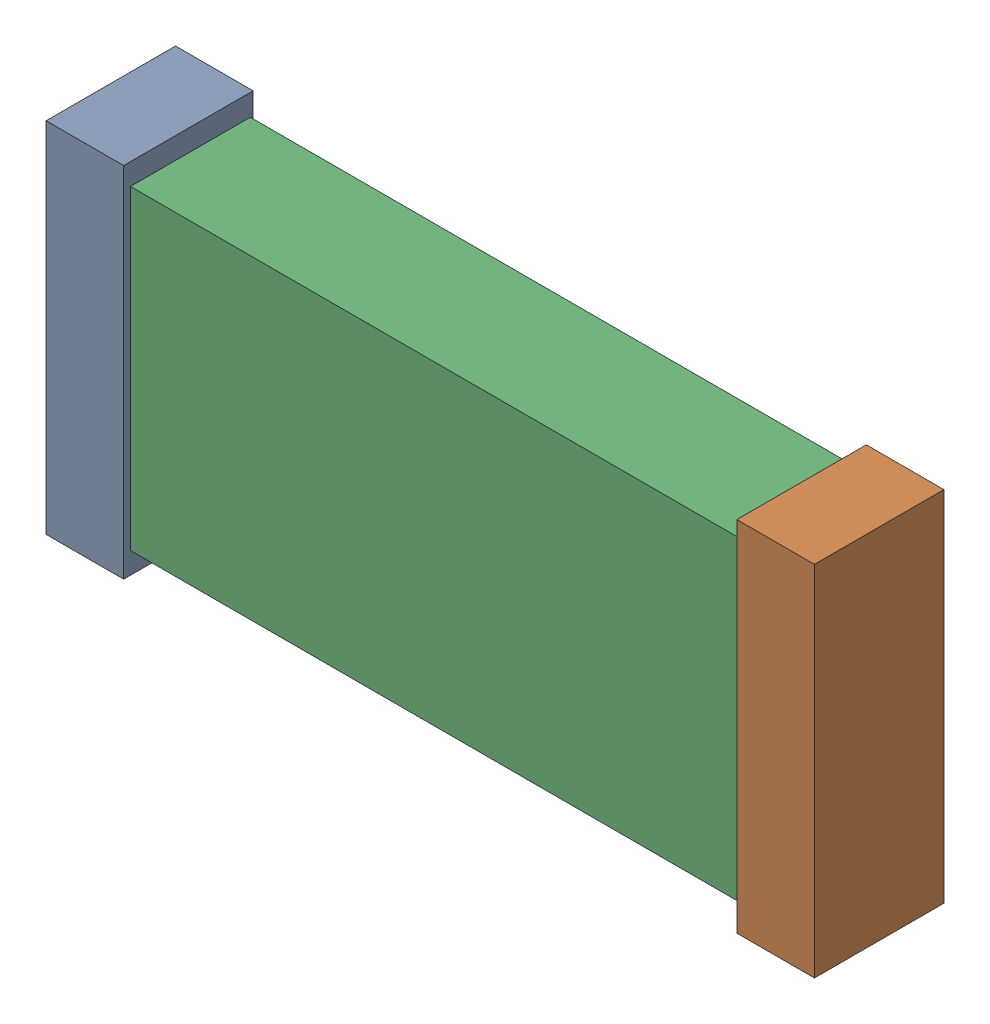
SolidWorks assembly C11, configuration Default. Lengths in mm.
Overall size (2.72 1.27 0.46).
6 component instances, 2 part files, 0 mates.
Components (placement in the parent):
- 432117136-1: 432117136 [Default] at (42.9816 12.0083 -0.8715) size (0.28 1.27 0.46)
  - Extruded (25)-1: Extruded (25) [Default] at origin size (0.28 1.27 0.46)
- 432117136_1-1: 432117136_1 [Default] at (45.4305 12.0083 -0.8715) size (0.28 1.27 0.46)
  - Extruded (25)-1: Extruded (25) [Default] at origin size (0.28 1.27 0.46)
- 432120848-1: 432120848 [Default] at (44.15 12.0083 -0.8615) size (2.29 1.12 0.42)
  - Extruded (26)-1: Extruded (26) [Default] at origin size (2.29 1.12 0.42)
